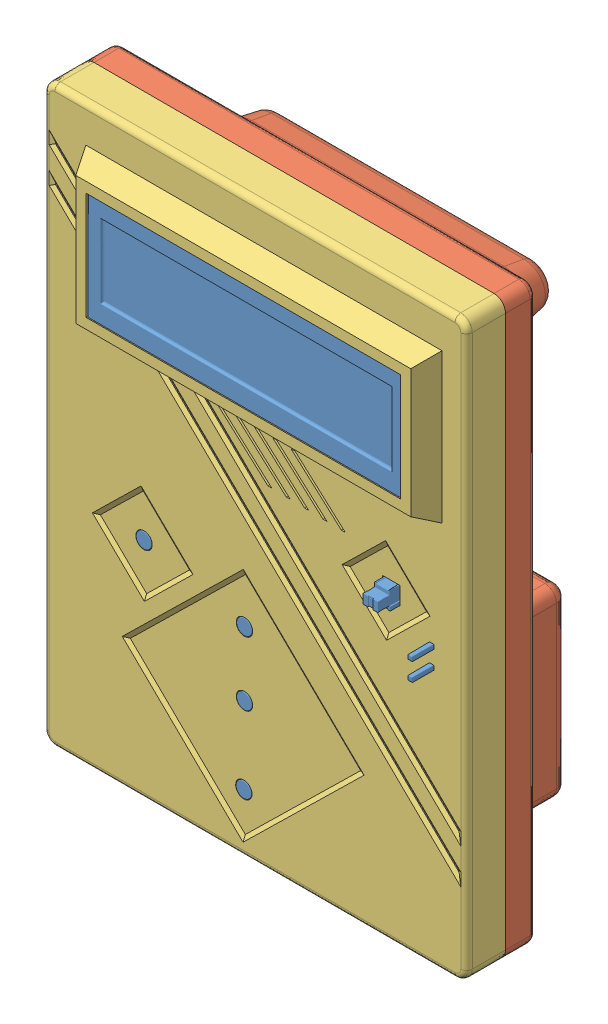
SolidWorks assembly Assem_bottom, configuration Default. Lengths in mm.
Overall size (368.39 500 150.5).
3 component instances, 3 part files, 8 mates.
Components (placement in the parent):
- OBJ_VoiceRecorderFInalPCB-1: OBJ_VoiceRecorderFInalPCB [Default] at origin size (347.27 455.3 76.67) (hidden)
- Bottom Part^Assem_bottom-1: Bottom Part^Assem_bottom [Default] at origin size (368.39 500 103.75) (virtual)
- Top Part^Assem_bottom-1: Top Part^Assem_bottom [Default] at origin size (368.39 500 52) (virtual)
Mates (geometry in assembly coordinates):
- InPlace2: in place: plane of ? through (0 0 0) normal (0 0 1); moOrthogonalPlaneRef_w of ? through (0 0 0) normal (0 1 0); plane of ? through (0 0 0) normal (1 0 0); unknown of ?
- Coincident4: coincident aligned: 
- Coincident5: coincident aligned: plane of Part3^Assem_bottom-1 through (0 0 0) normal (0 1 0)
- Coincident6: coincident anti-aligned: plane of Part3^Assem_bottom-1 through (0 0 0) normal (1 0 0)
- InPlace3: in place: plane of ? through (0 0 0) normal (0 0 1); plane of ? through (0 0 0) normal (0 1 0); plane of ? through (0 0 0) normal (1 0 0); unknown of ?
- Coincident1: coincident aligned: 
- Coincident2: coincident aligned: plane of Top Part^Assem_bottom-1 through (0 0 0) normal (0 1 0)
- Coincident3: coincident anti-aligned: plane of Top Part^Assem_bottom-1 through (0 0 0) normal (1 0 0)
